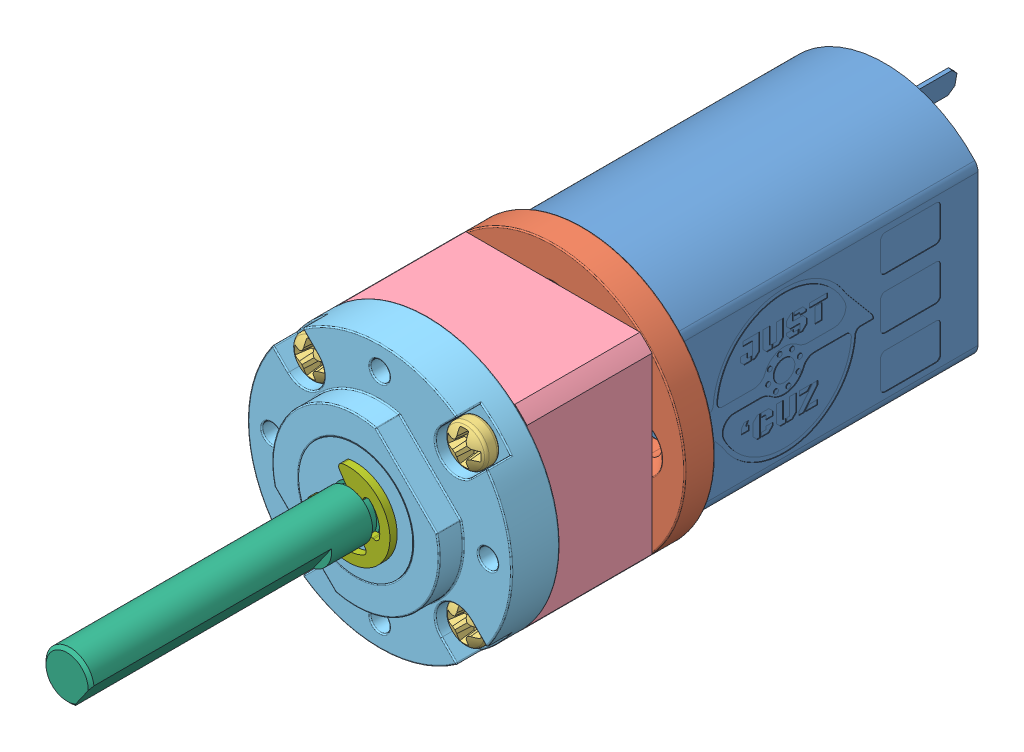
SolidWorks assembly DartBox-V2-Drive, configuration Default. Lengths in mm.
Overall size (26.86 26.86 72.3).
15 component instances, 7 part files, 0 mates.
Components (placement in the parent):
- DartBox+V2+Drive+-+Just+'Cuz+Robotics.igs-1: DartBox+V2+Drive+-+Just+'Cuz+Robotics.igs [Default] at origin size (26.86 26.86 72.3)
  - DartBox 130 motor v14.igs-1: DartBox 130 motor v14.igs [Default] at (0.1107 15.4459 54.2565) x (1 0 0) z (0 0 -1) size (15.5 20.4 34.9)
  - DartBox V2 Drive Gearbox v36.igs-1: DartBox V2 Drive Gearbox v36.igs [Default] at (0.1107 15.4459 54.2565) x (0 1 0) z (0 0 1) size (26.86 26.86 42.9)
    - Motor Mount Plate.igs-1: Motor Mount Plate.igs [Default] at (0 0 2.5) x (1 0 0) z (0 -1 0) size (21.95 3.5 21.95)
    - Screws M2 x 14mm.igs-1: Screws M2 x 14mm.igs [Default] at (6.364 6.364 0.9) size (3.4 3.84 17.02)
    - Screws M2 x 14mm.igs-2: Screws M2 x 14mm.igs [Default] at (-6.364 6.364 0.9) x (0 1 0) z (0 0 1) size (3.4 3.84 17.02)
    - Screws M2 x 14mm.igs-3: Screws M2 x 14mm.igs [Default] at (-6.364 -6.364 0.9) x (-1 0 0) z (0 0 1) size (3.4 3.84 17.02)
    - Screws M2 x 14mm.igs-4: Screws M2 x 14mm.igs [Default] at (6.364 -6.364 0.9) x (0 -1 0) z (0 0 1) size (3.4 3.84 17.02)
    - Ring Gear.igs-1: Ring Gear.igs [Default] at (-10.1305 0.1259 -54.0061) x (0 -1 0) z (0 0 1) size (26.86 26.86 40.4)
      - Ring Gear Body.igs-1: Ring Gear Body.igs [Default] at (0.1259 10.1305 56.5061) x (0 1 0) z (1 0 0) size (16.5 10.4 16.5)
      - Front Plate.igs-1: Front Plate.igs [Default] at (0.1259 10.1305 56.5061) x (0 1 0) z (1 0 0) size (26.86 30.5 26.86)
        - Front Plate-0.igs-1: Front Plate-0.igs [Default] at origin size (26.86 6.5 26.86)
        - Shaft.igs-1: Shaft.igs [Default] x (-0.819152 0 -0.573576) z (0.573576 0 -0.819152) size (9.67 30.3 7.35)
          - Shaft-1.igs-1: Shaft-1.igs [Default] at origin size (4.54 30.3 4.98)
          - 98543A103_Side-Mount External Retaining Rings.igs-1: 98543A103_Side-Mount External Retaining Rings.igs [Default] at (0 16.7 0) x (0 1 0) z (0 0 1) size (0.6 9.67 7.35)
